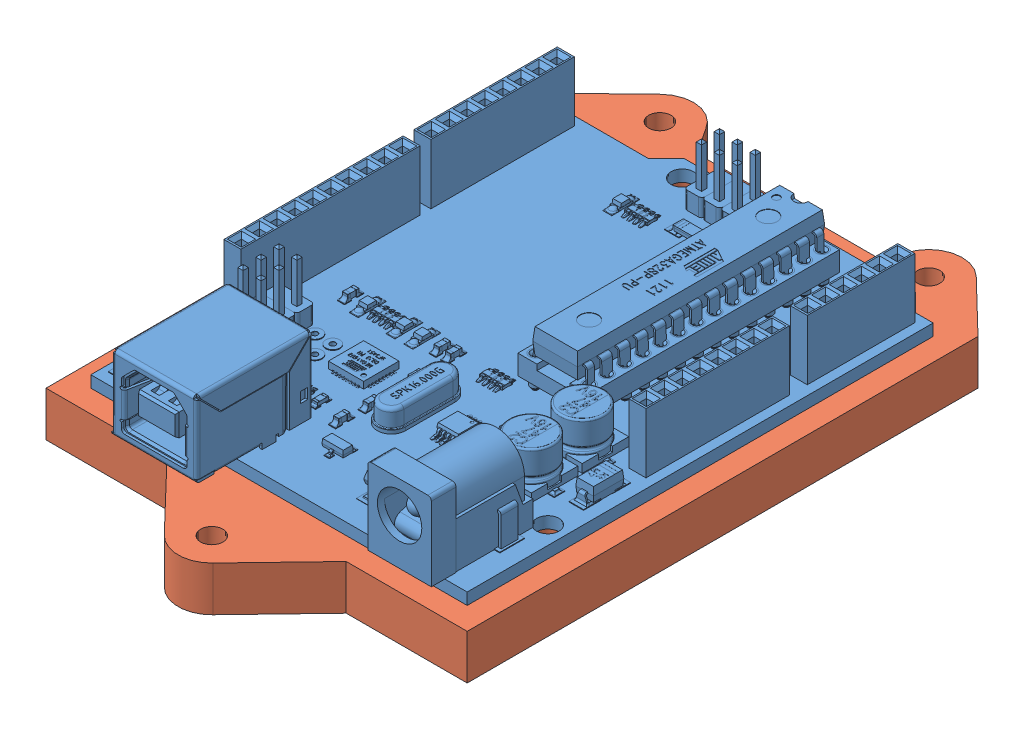
SolidWorks assembly temp, configuration Default. Lengths in mm.
Overall size (59.69 19.05 92.08).
2 component instances, 2 part files, 4 mates.
Components (placement in the parent):
- Arduino Uno-1: Arduino Uno [Default] at (35.7978 22.6375 0.4915) size (53.34 15.25 74.93)
- Arduino Adapter-1: Arduino Adapter [Default] at (35.7978 20.9875 0.4915) x (-1 0 0) z (0 -1 0) size (59.69 92.07 6.35)
Mates (geometry in assembly coordinates):
- InPlace1: in place: plane of ? through (29.1596 30.2204 5.8221) normal (0 -1 0); plane of ? through (0 30.2204 0) normal (0 -1 0); moOrthogonalPlaneRef_w of ? through (29.1596 30.2204 5.8221) normal (0 -1 0); unknown of ?; plane of ? through (29.1596 30.2204 5.8221) normal (0 -1 0); line of ? through (-55 0 30.2204) axis (0 -1 0); plane of Arduino Uno-1 through (35.7978 20.9875 0.4915) normal (0 -1 0); unknown of Arduino Adapter-1
- Coincident1: coincident aligned: plane of Arduino Uno-1; plane of Arduino Adapter-1
- Coincident2: coincident aligned: moOrthogonalPlaneRef_w of Arduino Uno-1 through (35.7978 20.9875 0.4915) normal (0 0 -1); plane of Arduino Adapter-1
- Coincident3: coincident anti-aligned: moOrthogonalPlaneRef_w of Arduino Uno-1 through (35.7978 20.9875 0.4915) normal (1 0 0); plane of Arduino Adapter-1
